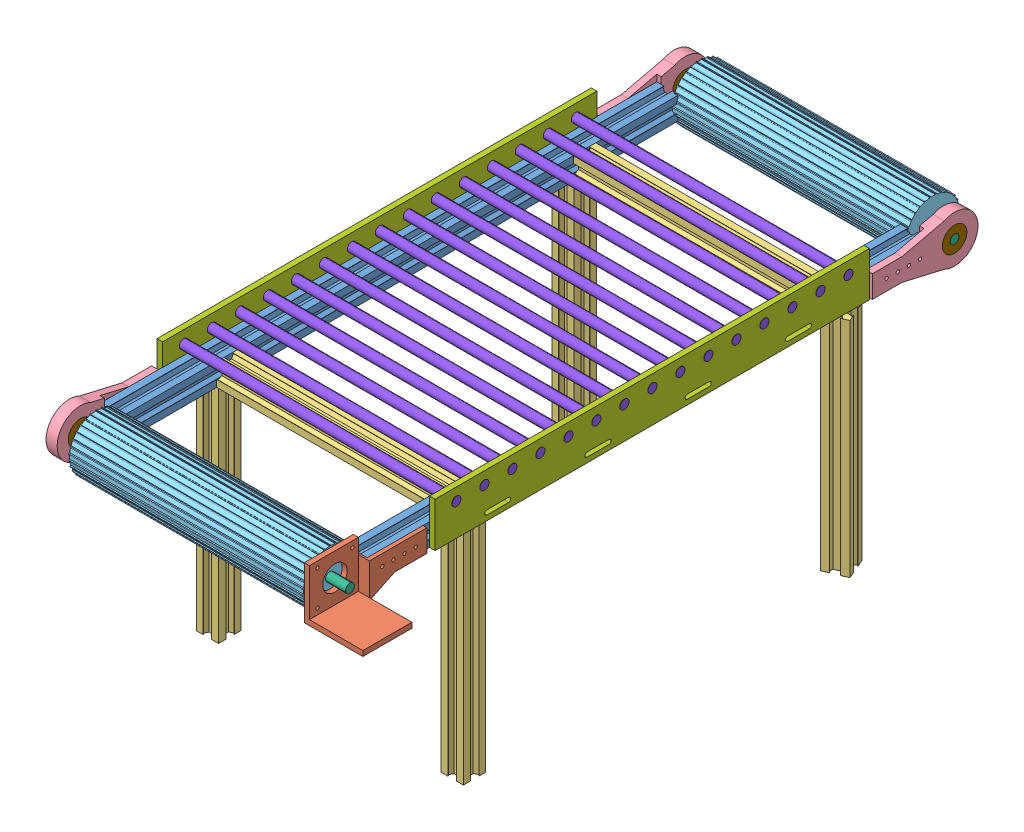
SolidWorks assembly Montaj1, configuration Varsayılan. Lengths in mm.
Overall size (287.6 244.9 612.03).
36 component instances, 9 part files, 73 mates.
Components (placement in the parent):
- 20X20X50SİGMA-1: 20X20X50SİGMA [Varsayılan] at (-638.009 -147.3543 983.6893) size (20 20 500)
- motor-1: motor [Varsayılan] at (-628.009 -147.3543 1458.6893) x (0 0 -1) z (1 0 0) size (95.5 46.7 57.6)
- 20X20X20SİGMA-1: 20X20X20SİGMA [Varsayılan] at (-648.009 -147.3543 1388.8412) x (0 0 -1) z (-1 0 0) size (20 20 200)
- 20X20X20SİGMA-2: 20X20X20SİGMA [Varsayılan] at (-848.009 -147.3543 1068.5043) x (0 0 -1) z (1 0 0) size (20 20 200)
- 20X20X50SİGMA-2: 20X20X50SİGMA [Varsayılan] at (-858.009 -147.3543 983.6893) size (20 20 500)
- 20X20X20SİGMA-4: 20X20X20SİGMA [Varsayılan] at (-858.009 -357.3543 1387.1369) x (0 0 -1) z (0 1 0) size (20 20 200)
- 20X20X20SİGMA-9: 20X20X20SİGMA [Varsayılan] at (-858.009 -357.3543 1067.9779) x (0 0 -1) z (0 1 0) size (20 20 200)
- 20X20X20SİGMA-10: 20X20X20SİGMA [Varsayılan] at (-628.8498 -357.3543 1057.216) x (-0.921419 0 0.388571) z (0 1 0) size (20 20 200)
- 20X20X20SİGMA-11: 20X20X20SİGMA [Varsayılan] at (-638.009 -357.3543 1387.3318) x (0 0 -1) z (0 1 0) size (20 20 200)
- MİLTUTUCU-1: MİLTUTUCU [Varsayılan] at (-874.009 -147.3543 1457.7093) x (0 0 -1) z (1 0 0) size (94.8 42 10)
- MİLTUTUCU-2: MİLTUTUCU [Varsayılan] at (-622.009 -147.3543 1009.6693) x (0 0 1) z (-1 0 0) size (94.8 42 10)
- MİLTUTUCU-3: MİLTUTUCU [Varsayılan] at (-874.009 -147.3543 1009.6693) x (0 0 1) z (1 0 0) size (94.8 42 10)
- MİL-3: MİL [Varsayılan] at (-775.3973 -127.6018 1518.5203) x (1 0 0) z (0 -0.561715 0.827331) size (210 49.37 49.37)
- MİL-4: MİL [Varsayılan] at (-776.9261 -130.2575 945.6046) x (1 0 0) z (0 0.697998 0.7161) size (210 49.37 49.37)
- mill-2: mill [Varsayılan] at (-874.009 -147.3543 962.2693) x (0 0.860654 -0.509189) z (1 0 0) size (7.95 7.95 252)
- mill-3: mill [Varsayılan] at (-622.009 -147.3543 1505.1093) x (0 0.39642 0.918069) z (-1 0 0) size (7.95 7.95 252)
- üst mil tutucu-1: üst mil tutucu [Varsayılan] at (-867.719 -117.3543 1427.752) x (0 0 1) z (-1 0 0) size (390 40 5)
- üst mil tutucu-2: üst mil tutucu [Varsayılan] at (-628.009 -117.3543 1037.8017) x (0 0 -1) z (1 0 0) size (390 40 5)
- üst mil-1: üst mil [Varsayılan] at (-622.719 -128.3543 1408.752) x (0 0.760069 0.649842) z (-1 0 0) size (8 8 250)
- üst mil-2: üst mil [Varsayılan] at (-622.719 -128.3543 1383.6091) x (0 0.724737 0.689026) z (-1 0 0) size (8 8 250)
- üst mil-3: üst mil [Varsayılan] at (-872.719 -128.3543 1358.4663) x (0 0 -1) z (1 0 0) size (8 8 250)
- üst mil-4: üst mil [Varsayılan] at (-872.719 -128.3543 1333.3234) x (0 0 -1) z (1 0 0) size (8 8 250)
- üst mil-5: üst mil [Varsayılan] at (-872.719 -128.3543 1308.1806) x (0 0 -1) z (1 0 0) size (8 8 250)
- üst mil-6: üst mil [Varsayılan] at (-872.719 -128.3543 1182.4663) x (0 0 -1) z (1 0 0) size (8 8 250)
- üst mil-7: üst mil [Varsayılan] at (-872.719 -128.3543 1157.3234) x (0 0 -1) z (1 0 0) size (8 8 250)
- üst mil-8: üst mil [Varsayılan] at (-872.719 -128.3543 1107.0377) x (0 0 -1) z (1 0 0) size (8 8 250)
- üst mil-9: üst mil [Varsayılan] at (-872.719 -128.3543 1132.1806) x (0 0 -1) z (1 0 0) size (8 8 250)
- üst mil-10: üst mil [Varsayılan] at (-872.719 -128.3543 1232.752) x (0 0 -1) z (1 0 0) size (8 8 250)
- üst mil-11: üst mil [Varsayılan] at (-872.719 -128.3543 1257.8949) x (0 0 -1) z (1 0 0) size (8 8 250)
- üst mil-12: üst mil [Varsayılan] at (-872.719 -128.3543 1056.752) x (0 0 -1) z (1 0 0) size (8 8 250)
- üst mil-13: üst mil [Varsayılan] at (-872.719 -128.3543 1081.8949) x (0 0 -1) z (1 0 0) size (8 8 250)
- üst mil-14: üst mil [Varsayılan] at (-872.719 -128.3543 1207.6091) x (0 0 -1) z (1 0 0) size (8 8 250)
- üst mil-15: üst mil [Varsayılan] at (-872.719 -128.3543 1283.0377) x (0 0 -1) z (1 0 0) size (8 8 250)
- rulman-1: rulman [Varsayılan] at (-874.009 -147.3543 1505.1093) x (0 -0.445763 -0.895151) z (1 0 0) size (22 22 10)
- rulman-2: rulman [Varsayılan] at (-864.009 -147.3543 962.2693) x (0 0.202409 0.979301) z (-1 0 0) size (22 22 10)
- rulman-3: rulman [Varsayılan] at (-622.009 -147.3543 962.2693) x (0 -0.493297 0.869861) z (-1 0 0) size (22 22 10)
Mates (geometry in assembly coordinates):
- Çakışık1: coincident anti-aligned: plane of 20X20X50SİGMA-1 through (-638.009 -147.3543 1483.6893) normal (0 0 1); plane of motor-1 through (-628.009 -147.3543 1483.6893) normal (0 0 -1)
- Çakışık2: coincident anti-aligned: plane of 20X20X50SİGMA-1 through (-628.009 -137.3543 1483.6893) normal (1 0 0); plane of motor-1 through (-628.009 -147.3543 1458.6893) normal (-1 0 0)
- Çakışık3: coincident aligned: plane of 20X20X50SİGMA-1 through (-632.2628 -137.3543 1483.6893) normal (0 1 0); plane of motor-1 through (-624.509 -137.3543 1483.6893) normal (0 1 0)
- Çakışık5: coincident anti-aligned: plane of 20X20X50SİGMA-1 through (-648.009 -137.3543 1483.6893) normal (-1 0 0); plane of 20X20X20SİGMA-1 through (-648.009 -147.3543 1388.8412) normal (1 0 0)
- Çakışık6: coincident aligned: plane of 20X20X50SİGMA-1 through (-648.009 -137.3543 1483.6893) normal (0 1 0); plane of 20X20X20SİGMA-1 through (-848.009 -137.3543 1398.8412) normal (0 1 0)
- Çakışık7: coincident anti-aligned: plane of 20X20X50SİGMA-1 through (-648.009 -137.3543 1483.6893) normal (-1 0 0); plane of 20X20X20SİGMA-2 through (-648.009 -147.3543 1068.5043) normal (1 0 0)
- Çakışık8: coincident aligned: plane of 20X20X50SİGMA-1 through (-648.009 -137.3543 1483.6893) normal (0 1 0); plane of 20X20X20SİGMA-2 through (-648.009 -137.3543 1078.5043) normal (0 1 0)
- Çakışık9: coincident anti-aligned: plane of 20X20X20SİGMA-2 through (-848.009 -147.3543 1068.5043) normal (-1 0 0); plane of 20X20X50SİGMA-2 through (-848.009 -137.3543 1483.6893) normal (1 0 0)
- Çakışık10: coincident aligned: plane of 20X20X50SİGMA-1 through (-638.009 -147.3543 1483.6893) normal (0 0 1); plane of 20X20X50SİGMA-2 through (-858.009 -147.3543 1483.6893) normal (0 0 1)
- Çakışık11: coincident aligned: plane of 20X20X20SİGMA-2 through (-648.009 -137.3543 1062.758) normal (0 1 0); plane of 20X20X50SİGMA-2 through (-852.2628 -137.3543 1483.6893) normal (0 1 0)
- Çakışık15: coincident aligned: plane of 20X20X50SİGMA-2 through (-868.009 -152.8043 1483.6893) normal (-1 0 0); plane of 20X20X20SİGMA-4 through (-868.009 -157.3543 1381.3907) normal (-1 0 0)
- Çakışık16: coincident anti-aligned: plane of 20X20X50SİGMA-2 through (-868.009 -157.3543 1483.6893) normal (0 -1 0); plane of 20X20X20SİGMA-4 through (-858.009 -157.3543 1387.1369) normal (0 1 0)
- Çakışık17: coincident aligned: plane of 20X20X50SİGMA-2 through (-868.009 -152.8043 1483.6893) normal (-1 0 0); plane of 20X20X20SİGMA-9 through (-868.009 -157.3543 1062.2316) normal (-1 0 0)
- Çakışık18: coincident anti-aligned: plane of 20X20X50SİGMA-2 through (-868.009 -157.3543 1483.6893) normal (0 -1 0); plane of 20X20X20SİGMA-9 through (-858.009 -157.3543 1067.9779) normal (0 1 0)
- Çakışık19: coincident aligned: plane of 20X20X50SİGMA-1 through (-628.009 -152.8043 1483.6893) normal (1 0 0); plane of 20X20X20SİGMA-11 through (-628.009 -157.3543 1381.5855) normal (1 0 0)
- Çakışık20: coincident anti-aligned: plane of 20X20X50SİGMA-1 through (-632.2628 -157.3543 1483.6893) normal (0 -1 0); plane of 20X20X20SİGMA-11 through (-638.009 -157.3543 1387.3318) normal (0 1 0)
- Çakışık21: coincident: plane of 20X20X50SİGMA-1 through (-628.009 -152.8043 1483.6893) normal (1 0 0); line of 20X20X20SİGMA-10 through (-628.009 -357.3543 1046.3287) axis (0 1 0)
- Çakışık22: coincident anti-aligned: plane of 20X20X50SİGMA-1 through (-648.009 -157.3543 1483.6893) normal (0 -1 0); plane of 20X20X20SİGMA-10 through (-628.8498 -157.3543 1057.216) normal (0 1 0)
- Çakışık23: coincident aligned: plane of 20X20X50SİGMA-2 through (-868.009 -137.3543 1483.6893) normal (0 1 0); plane of MİLTUTUCU-1 through (-864.009 -137.3543 1457.7093) normal (0 1 0)
- Çakışık24: coincident anti-aligned: plane of 20X20X50SİGMA-2 through (-868.009 -137.3543 1483.6893) normal (-1 0 0); plane of MİLTUTUCU-1 through (-868.009 -147.3543 1457.7093) normal (1 0 0)
- Çakışık25: coincident anti-aligned: plane of 20X20X50SİGMA-2 through (-858.009 -147.3543 1483.6893) normal (0 0 1); plane of MİLTUTUCU-1 through (-868.009 -131.3252 1483.6893) normal (0 0 -1)
- Çakışık26: coincident aligned: plane of 20X20X50SİGMA-1 through (-632.2628 -137.3543 1483.6893) normal (0 1 0); plane of MİLTUTUCU-2 through (-632.009 -137.3543 1009.6693) normal (0 1 0)
- Çakışık27: coincident anti-aligned: plane of 20X20X50SİGMA-1 through (-638.009 -147.3543 983.6893) normal (0 0 -1); plane of MİLTUTUCU-2 through (-628.009 -131.3252 983.6893) normal (0 0 1)
- Çakışık28: coincident anti-aligned: plane of 20X20X50SİGMA-1 through (-628.009 -137.3543 1483.6893) normal (1 0 0); plane of MİLTUTUCU-2 through (-628.009 -147.3543 1009.6693) normal (-1 0 0)
- Çakışık29: coincident aligned: plane of 20X20X50SİGMA-2 through (-868.009 -137.3543 1483.6893) normal (0 1 0); plane of MİLTUTUCU-3 through (-864.009 -137.3543 1009.6693) normal (0 1 0)
- Çakışık30: coincident anti-aligned: plane of 20X20X50SİGMA-2 through (-858.009 -147.3543 983.6893) normal (0 0 -1); plane of MİLTUTUCU-3 through (-868.009 -163.3835 983.6893) normal (0 0 1)
- Çakışık31: coincident anti-aligned: plane of 20X20X50SİGMA-2 through (-868.009 -137.3543 1483.6893) normal (-1 0 0); plane of MİLTUTUCU-3 through (-868.009 -147.3543 1009.6693) normal (1 0 0)
- Eş Merkezli1: concentric anti-aligned: cylinder of MİLTUTUCU-3 through (-933.009 -147.3543 962.2693) axis (1 0 0) radius 11.025; cylinder of mill-2 through (-622.009 -147.3543 962.2693) axis (-1 0 0) radius 3.975
- Çakışık32: coincident anti-aligned: plane of MİLTUTUCU-3 through (-874.009 -147.3543 962.2693) normal (-1 0 0); circle of mill-2
- Eş Merkezli3: concentric anti-aligned: cylinder of MİL-4 through (-921.5575 -147.3543 962.2693) axis (1 0 0) radius 3.995; cylinder of mill-2 through (-622.009 -147.3543 962.2693) axis (-1 0 0) radius 3.975
- Eş Merkezli4: concentric aligned: circle of MİLTUTUCU-1; cylinder of mill-3 through (-874.009 -147.3543 1505.1093) axis (1 0 0) radius 3.975
- Çakışık33: coincident aligned: plane of MİLTUTUCU-1 through (-874.009 -147.3543 1505.1093) normal (-1 0 0); plane of mill-3 through (-874.009 -147.3543 1505.1093) normal (-1 0 0)
- Eş Merkezli5: concentric aligned: cylinder of MİL-3 through (-920.0287 -147.3543 1505.1093) axis (1 0 0) radius 3.995; cylinder of mill-3 through (-874.009 -147.3543 1505.1093) axis (1 0 0) radius 3.975
- Çakışık34: coincident: line of 20X20X50SİGMA-2 through (-867.719 -142.0543 983.6893) axis (0 0 1); plane of üst mil tutucu-1 through (-867.719 -117.3543 1427.752) normal (1 0 0)
- Çakışık35: coincident aligned: plane of 20X20X50SİGMA-2 through (-868.009 -157.3543 1483.6893) normal (0 -1 0); plane of üst mil tutucu-1 through (-872.719 -157.3543 1427.752) normal (0 -1 0)
- Çakışık36: coincident anti-aligned: plane of 20X20X50SİGMA-1 through (-628.009 -152.8043 1483.6893) normal (1 0 0); plane of üst mil tutucu-2 through (-628.009 -117.3543 1037.8017) normal (-1 0 0)
- Çakışık37: coincident aligned: plane of 20X20X50SİGMA-1 through (-632.2628 -157.3543 1483.6893) normal (0 -1 0); plane of üst mil tutucu-2 through (-623.009 -157.3543 1037.8017) normal (0 -1 0)
- Eş Merkezli6: concentric aligned: cylinder of üst mil tutucu-1 through (-872.719 -128.3543 1408.752) axis (1 0 0) radius 4; cylinder of üst mil-1 through (-872.719 -128.3543 1408.752) axis (1 0 0) radius 4
- Çakışık38: coincident aligned: plane of üst mil tutucu-1 through (-872.719 -117.3543 1427.752) normal (-1 0 0); plane of üst mil-1 through (-872.719 -128.3543 1408.752) normal (-1 0 0)
- Çakışık39: coincident anti-aligned: circle of üst mil tutucu-1; cylinder of üst mil-2 through (-872.719 -128.3543 1383.6091) axis (1 0 0) radius 4
- Çakışık40: coincident aligned: plane of üst mil tutucu-1 through (-872.719 -117.3543 1427.752) normal (-1 0 0); circle of üst mil-2
- Eş Merkezli7: concentric anti-aligned: cylinder of üst mil tutucu-1 through (-872.719 -128.3543 1358.4663) axis (1 0 0) radius 4; cylinder of üst mil-3 through (-622.719 -128.3543 1358.4663) axis (-1 0 0) radius 4
- Çakışık41: coincident aligned: plane of üst mil tutucu-1 through (-872.719 -117.3543 1427.752) normal (-1 0 0); plane of üst mil-3 through (-872.719 -128.3543 1358.4663) normal (-1 0 0)
- Eş Merkezli8: concentric anti-aligned: cylinder of üst mil tutucu-1 through (-872.719 -128.3543 1333.3234) axis (1 0 0) radius 4; cylinder of üst mil-4 through (-622.719 -128.3543 1333.3234) axis (-1 0 0) radius 4
- Çakışık42: coincident aligned: plane of üst mil tutucu-1 through (-872.719 -117.3543 1427.752) normal (-1 0 0); plane of üst mil-4 through (-872.719 -128.3543 1333.3234) normal (-1 0 0)
- Eş Merkezli9: concentric anti-aligned: cylinder of üst mil tutucu-1 through (-872.719 -128.3543 1308.1806) axis (1 0 0) radius 4; cylinder of üst mil-5 through (-622.719 -128.3543 1308.1806) axis (-1 0 0) radius 4
- Çakışık43: coincident anti-aligned: plane of üst mil tutucu-1 through (-872.719 -117.3543 1427.752) normal (-1 0 0); circle of üst mil-5
- Eş Merkezli10: concentric anti-aligned: cylinder of üst mil tutucu-1 through (-872.719 -128.3543 1283.0377) axis (1 0 0) radius 4; cylinder of üst mil-15 through (-622.719 -128.3543 1283.0377) axis (-1 0 0) radius 4
- Çakışık44: coincident aligned: plane of üst mil tutucu-1 through (-872.719 -117.3543 1427.752) normal (-1 0 0); plane of üst mil-15 through (-872.719 -128.3543 1283.0377) normal (-1 0 0)
- Eş Merkezli11: concentric anti-aligned: cylinder of üst mil tutucu-1 through (-872.719 -128.3543 1257.8949) axis (1 0 0) radius 4; cylinder of üst mil-11 through (-622.719 -128.3543 1257.8949) axis (-1 0 0) radius 4
- Çakışık45: coincident aligned: circle of üst mil tutucu-1; plane of üst mil-11 through (-872.719 -128.3543 1257.8949) normal (-1 0 0)
- Eş Merkezli12: concentric anti-aligned: cylinder of üst mil tutucu-1 through (-872.719 -128.3543 1232.752) axis (1 0 0) radius 4; cylinder of üst mil-10 through (-622.719 -128.3543 1232.752) axis (-1 0 0) radius 4
- Çakışık46: coincident aligned: plane of üst mil tutucu-1 through (-872.719 -117.3543 1427.752) normal (-1 0 0); plane of üst mil-10 through (-872.719 -128.3543 1232.752) normal (-1 0 0)
- Eş Merkezli13: concentric anti-aligned: cylinder of üst mil tutucu-1 through (-872.719 -128.3543 1207.6091) axis (1 0 0) radius 4; cylinder of üst mil-14 through (-622.719 -128.3543 1207.6091) axis (-1 0 0) radius 4
- Çakışık47: coincident aligned: plane of üst mil tutucu-1 through (-872.719 -117.3543 1427.752) normal (-1 0 0); plane of üst mil-14 through (-872.719 -128.3543 1207.6091) normal (-1 0 0)
- Eş Merkezli14: concentric anti-aligned: cylinder of üst mil tutucu-1 through (-872.719 -128.3543 1182.4663) axis (1 0 0) radius 4; cylinder of üst mil-6 through (-622.719 -128.3543 1182.4663) axis (-1 0 0) radius 4
- Çakışık48: coincident aligned: plane of üst mil tutucu-1 through (-872.719 -117.3543 1427.752) normal (-1 0 0); plane of üst mil-6 through (-872.719 -128.3543 1182.4663) normal (-1 0 0)
- Eş Merkezli15: concentric anti-aligned: cylinder of üst mil tutucu-1 through (-872.719 -128.3543 1157.3234) axis (1 0 0) radius 4; cylinder of üst mil-7 through (-622.719 -128.3543 1157.3234) axis (-1 0 0) radius 4
- Çakışık49: coincident aligned: plane of üst mil tutucu-1 through (-872.719 -117.3543 1427.752) normal (-1 0 0); plane of üst mil-7 through (-872.719 -128.3543 1157.3234) normal (-1 0 0)
- Eş Merkezli16: concentric anti-aligned: cylinder of üst mil tutucu-1 through (-872.719 -128.3543 1132.1806) axis (1 0 0) radius 4; cylinder of üst mil-9 through (-622.719 -128.3543 1132.1806) axis (-1 0 0) radius 4
- Çakışık50: coincident anti-aligned: plane of üst mil tutucu-1 through (-872.719 -117.3543 1427.752) normal (-1 0 0); circle of üst mil-9
- Eş Merkezli17: concentric anti-aligned: cylinder of üst mil tutucu-1 through (-872.719 -128.3543 1107.0377) axis (1 0 0) radius 4; cylinder of üst mil-8 through (-622.719 -128.3543 1107.0377) axis (-1 0 0) radius 4
- Çakışık51: coincident aligned: plane of üst mil tutucu-1 through (-872.719 -117.3543 1427.752) normal (-1 0 0); plane of üst mil-8 through (-872.719 -128.3543 1107.0377) normal (-1 0 0)
- Eş Merkezli18: concentric anti-aligned: cylinder of üst mil tutucu-1 through (-872.719 -128.3543 1081.8949) axis (1 0 0) radius 4; cylinder of üst mil-13 through (-622.719 -128.3543 1081.8949) axis (-1 0 0) radius 4
- Çakışık52: coincident aligned: circle of üst mil tutucu-1; plane of üst mil-13 through (-872.719 -128.3543 1081.8949) normal (-1 0 0)
- Eş Merkezli19: concentric anti-aligned: cylinder of üst mil tutucu-1 through (-872.719 -128.3543 1056.752) axis (1 0 0) radius 4; cylinder of üst mil-12 through (-622.719 -128.3543 1056.752) axis (-1 0 0) radius 4
- Çakışık53: coincident aligned: plane of üst mil tutucu-1 through (-872.719 -117.3543 1427.752) normal (-1 0 0); plane of üst mil-12 through (-872.719 -128.3543 1056.752) normal (-1 0 0)
- Eş Merkezli20: concentric anti-aligned: cylinder of MİLTUTUCU-1 through (-933.009 -147.3543 1505.1093) axis (1 0 0) radius 11.025; cylinder of rulman-1 through (-864.009 -147.3543 1505.1093) axis (-1 0 0) radius 11
- Çakışık54: coincident aligned: plane of MİLTUTUCU-1 through (-874.009 -147.3543 1505.1093) normal (-1 0 0); plane of rulman-1 through (-874.009 -147.3543 1505.1093) normal (-1 0 0)
- Çakışık55: coincident aligned: plane of MİLTUTUCU-3 through (-874.009 -147.3543 962.2693) normal (-1 0 0); plane of rulman-2 through (-874.009 -147.3543 962.2693) normal (-1 0 0)
- Eş Merkezli22: concentric aligned: cylinder of MİLTUTUCU-3 through (-933.009 -147.3543 962.2693) axis (1 0 0) radius 11.025; cylinder of rulman-2 through (-874.009 -147.3543 962.2693) axis (1 0 0) radius 11
- Çakışık56: coincident aligned: plane of MİLTUTUCU-2 through (-622.009 -147.3543 962.2693) normal (1 0 0); plane of rulman-3 through (-622.009 -147.3543 962.2693) normal (1 0 0)
- Eş Merkezli23: concentric anti-aligned: cylinder of MİLTUTUCU-2 through (-563.009 -147.3543 962.2693) axis (-1 0 0) radius 11.025; cylinder of rulman-3 through (-632.009 -147.3543 962.2693) axis (1 0 0) radius 11
